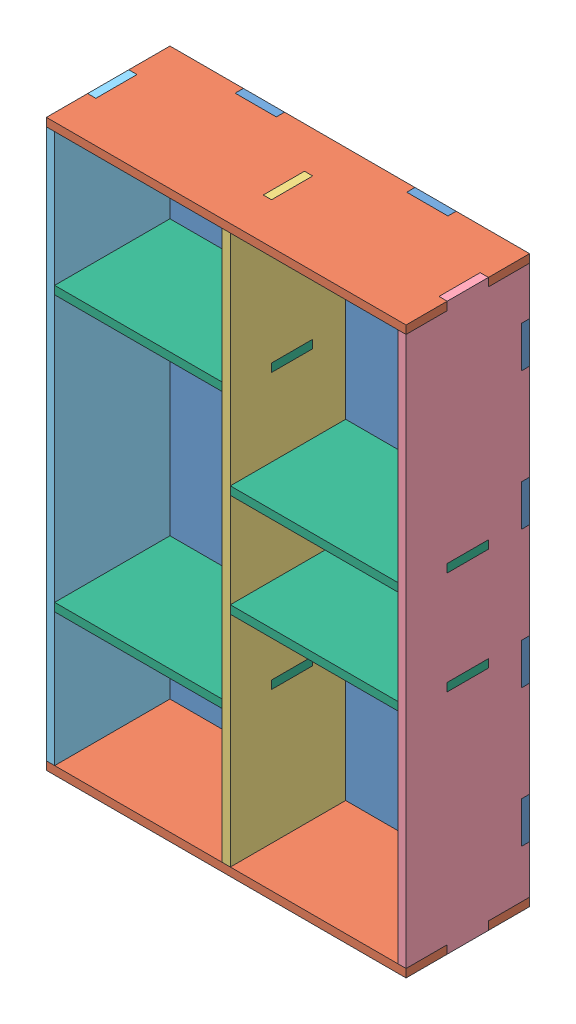
SolidWorks assembly Assem4, configuration Default. Lengths in mm.
Overall size (524 824 180).
10 component instances, 6 part files, 16 mates.
Components (placement in the parent):
- back-1: back [Default] at (305.1475 420.7567 634.058) size (524 824 12)
- bottom-1: bottom [Default] at (305.1475 8.7567 724.058) size (524 12 180)
- bottom-2: bottom [Default] at (305.1475 820.7567 724.058) size (524 12 180)
- center-2: center [Default] at (299.1475 420.7567 724.058) size (12 824 180)
- side3-5: side3 [Default] at (567.1475 420.7567 724.058) x (0 0 -1) z (-1 0 0) size (180 824 12)
- side2-4: side2 [Default] at (43.1475 420.7567 724.058) x (0 0 -1) z (1 0 0) size (180 824 12)
- spt-1: spt [Default] at (139.1475 614.7567 724.058) size (268 12 168)
- spt-2: spt [Default] at (139.1475 214.7567 724.058) size (268 12 168)
- spt-3: spt [Default] at (395.1475 489.7567 724.058) size (268 12 168)
- spt-4: spt [Default] at (395.1475 339.7567 724.058) size (268 12 168)
Mates (geometry in assembly coordinates):
- Coincident1: coincident: point of back-1; point of side2-4
- Coincident3: coincident: line of back-1 through (150.1475 8.7567 646.058) axis (1 0 0); point of bottom-1
- Coincident4: coincident: point of back-1; point of bottom-2
- Coincident8: coincident: point of bottom-1; point of center-2
- Coincident11: coincident: point of bottom-2; point of side3-5
- Coincident12: coincident: point of bottom-2; point of side2-4
- Coincident13: coincident: point of side2-4; point of spt-1
- Coincident14: coincident: point of back-1; point of center-2
- Coincident15: coincident: point of bottom-2; point of center-2
- Coincident16: coincident: point of bottom-1; point of center-2
- Coincident17: coincident: point of bottom-2; point of center-2
- Coincident19: coincident: point of side2-4; point of spt-2
- Coincident21: coincident: point of side3-5; point of ?
- Coincident22: coincident: point of side3-5; point of ?
- Coincident23: coincident: point of side3-5; point of spt-3
- Coincident24: coincident: point of side3-5; point of spt-4
